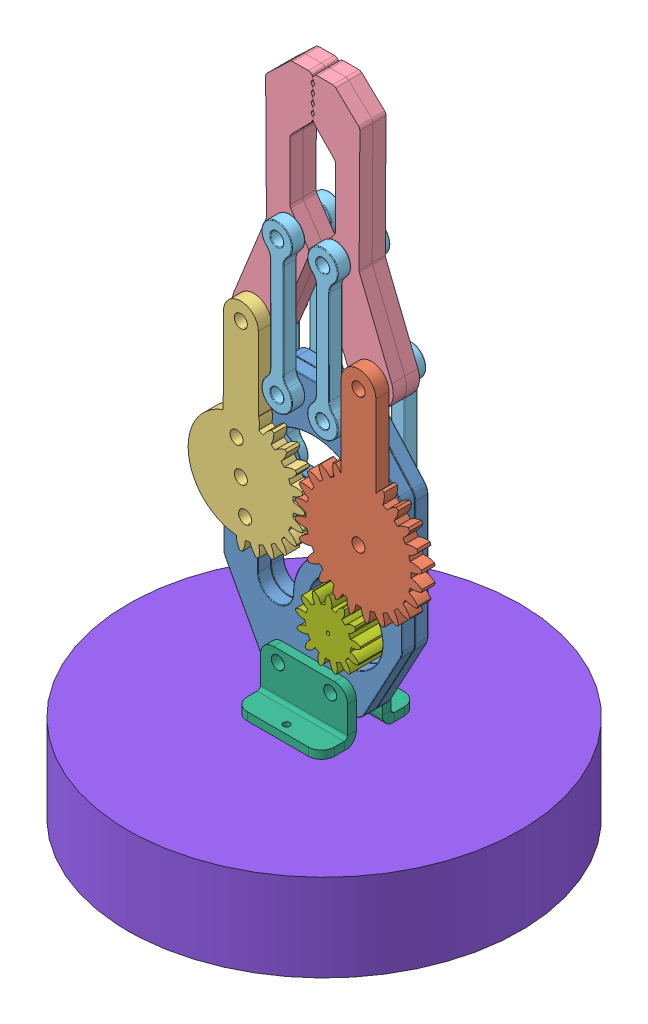
SolidWorks assembly Assem6, configuration Default. Lengths in mm.
Overall size (90 150.89 90).
26 component instances, 9 part files, 47 mates.
Components (placement in the parent):
- Part3-3-1: Part3-3 [Default] at origin size (41 62 3.03)
- part4-4-1: part4-4 [Default] at (13.5 37.5997 3) x (0 0 1) z (0 -1 0) size (3 29.07 49.54)
- part5-5-1: part5-5 [Default] at (-13.5 37.5997 6) x (0 0 -1) z (0.130526 -0.991445 0) size (3 26.63 49.27)
- Part1-1-1: Part1-1 [Default] at (-13.5 68.5997 0) x (0.374356 0.927285 0) z (0 0 1) size (60.3 20.75 3)
- Part2-2-1: Part2-2 [Default] at (-5.2398 58 4.5) x (-0.000786 1 0) z (0 0 1) size (38 7 3)
- Part2-2-2: Part2-2 [Default] at (5.2398 58 4.5) x (0.000786 1 0) z (0 0 1) size (38 7 3)
- Part1-1-2: Part1-1 [Default] at (13.5 68.5997 3) x (-0.374356 0.927285 0) z (0 0 -1) size (60.3 20.75 3)
- Part3-3-2: Part3-3 [Default] at (0 0 -3) size (41 62 3.03)
- Part1-1-3: Part1-1 [Default] at (13.5 68.5997 0) x (-0.374356 0.927285 0) z (0 0 -1) size (60.3 20.75 3)
- Part1-1-4: Part1-1 [Default] at (-13.5 68.5997 -3) x (0.374356 0.927285 0) z (0 0 1) size (60.3 20.75 3)
- Part2-2-5: Part2-2 [Default] at (-5.2398 58 -4.5) x (-0.000786 1 0) z (0 0 1) size (38 7 3)
- Part2-2-6: Part2-2 [Default] at (5.2398 58 -4.5) x (0.000786 1 0) z (0 0 1) size (38 7 3)
- Part2-2-9: Part2-2 [Default] at (13.5 37.5997 -4.5) x (0 1 0) z (0 0 1) size (38 7 3)
- Part2-2-10: Part2-2 [Default] at (-13.5 37.5997 -4.5) x (0 1 0) z (0 0 1) size (38 7 3)
- Part6-6-1: Part6-6 [Default] at (13.5 37.5997 7) x (1 0 0) z (0 1 0) (suppressed, hidden)
- Part7-7-1: Part7-7 [Default] at (0 -5.279 3) x (0 -1 0) z (-1 0 0) size (12 8 20)
- Part6-6-2: Part6-6 [Default] at (-13.5 37.5997 -7) x (-0.923728 -0.383049 0) z (-0.383049 0.923728 0) (suppressed, hidden)
- Part6-6-3: Part6-6 [Default] at (-31.0284 63.1684 -7) x (-0.923728 -0.383049 0) z (-0.383049 0.923728 0) (suppressed, hidden)
- Part6-6-4: Part6-6 [Default] at (-5.2398 58 -7) x (0.923728 0.383049 0) z (0.383049 -0.923728 0) (suppressed, hidden)
- Part6-6-5: Part6-6 [Default] at (-22.7772 83.5625 -7) x (0.923728 0.383049 0) z (0.383049 -0.923728 0) (suppressed, hidden)
- Part6-6-6: Part6-6 [Default] at (22.7772 83.5625 -7) x (0.923728 0.383049 0) z (0.383049 -0.923728 0) (suppressed, hidden)
- Part6-6-7: Part6-6 [Default] at (5.2398 58 -7) x (0.923728 0.383049 0) z (0.383049 -0.923728 0) (suppressed, hidden)
- Part6-6-8: Part6-6 [Default] at (31.0284 63.1684 -7) x (0.923728 0.383049 0) z (0.383049 -0.923728 0) (suppressed, hidden)
- Part7-7-3: Part7-7 [Default] at (0 -5.279 -3) x (0 -1 0) z (1 0 0) size (12 8 20)
- part8-8-1: part8-8 [Default] at (7.5 17.5997 7) x (0 0 -1) z (0.96731 -0.253595 0) size (13 17.5 17.5)
- Part7-1: Part7 [Default] at (1.0492 -25.1139 1.4412) size (90 20 90)
Mates (geometry in assembly coordinates):
- Concentric1: concentric aligned: cylinder of Part3-3-1 through (13.5 37.5997 3) axis (0 0 -1) radius 1.5; cylinder of part4-4-1 through (13.5 37.5997 53.0001) axis (0 0 -1) radius 1.5
- Coincident1: coincident anti-aligned: plane of Part3-3-1 through (0 0 3) normal (0 0 1); plane of part4-4-1 through (13.5 37.5997 3) normal (0 0 -1)
- Concentric2: concentric anti-aligned: cylinder of Part3-3-1 through (-13.5 37.5997 3) axis (0 0 -1) radius 1.5; cylinder of part5-5-1 through (-13.5 37.5997 -44.0001) axis (0 0 1) radius 1.5
- Coincident3: coincident anti-aligned: plane of Part3-3-1 through (0 0 3) normal (0 0 1); plane of part5-5-1 through (-13.5 37.5997 3) normal (0 0 -1)
- Concentric3: concentric aligned: cylinder of Part3-3-1 through (-5.2398 58 3) axis (0 0 -1) radius 1.5; cylinder of Part2-2-1 through (-5.2398 58 6) axis (0 0 -1) radius 1.5
- Coincident4: coincident anti-aligned: plane of Part3-3-1 through (0 0 3) normal (0 0 1); plane of Part2-2-1 through (-5.2398 58 3) normal (0 0 -1)
- Concentric4: concentric anti-aligned: cylinder of part5-5-1 through (-13.5 68.5997 3) axis (0 0 1) radius 1.5; cylinder of Part1-1-1 through (-13.5 68.5997 3) axis (0 0 -1) radius 1.5
- Concentric5: concentric aligned: cylinder of Part1-1-1 through (-5.2642 89 3) axis (0 0 -1) radius 1.5; cylinder of Part2-2-1 through (-5.2642 89 6) axis (0 0 -1) radius 1.5
- Concentric6: concentric anti-aligned: cylinder of part4-4-1 through (13.5 68.5997 6) axis (0 0 -1) radius 1.5; cylinder of Part1-1-2 through (13.5 68.5997 0) axis (0 0 1) radius 1.5
- Concentric7: concentric aligned: cylinder of Part3-3-1 through (5.2398 58 3) axis (0 0 -1) radius 1.5; cylinder of Part2-2-2 through (5.2398 58 6) axis (0 0 -1) radius 1.5
- Concentric8: concentric anti-aligned: cylinder of Part2-2-2 through (5.2642 89 6) axis (0 0 -1) radius 1.5; cylinder of Part1-1-2 through (5.2642 89 0) axis (0 0 1) radius 1.5
- Coincident8: coincident anti-aligned: plane of part4-4-1 through (13.5 37.5997 3) normal (0 0 -1); plane of Part1-1-2 through (13.5 68.5997 3) normal (0 0 1)
- Coincident9: coincident anti-aligned: plane of part5-5-1 through (-13.5 37.5997 3) normal (0 0 -1); plane of Part1-1-1 through (-13.5 68.5997 3) normal (0 0 1)
- Coincident10: coincident anti-aligned: plane of Part3-3-1 through (0 0 3) normal (0 0 1); plane of Part2-2-2 through (5.2398 58 3) normal (0 0 -1)
- Concentric11: concentric aligned: cylinder of Part3-3-2 through (13.5 37.5997 0) axis (0 0 -1) radius 1.5; cylinder of Part2-2-9 through (13.5 37.5997 -3) axis (0 0 -1) radius 1.5
- Concentric12: concentric anti-aligned: cylinder of Part1-1-3 through (13.5 68.5997 -3) axis (0 0 1) radius 1.5; cylinder of Part2-2-9 through (13.5 68.5997 -3) axis (0 0 -1) radius 1.5
- Coincident11: coincident anti-aligned: plane of Part3-3-2 through (0 0 -3) normal (0 0 -1); plane of Part2-2-9 through (13.5 37.5997 -3) normal (0 0 1)
- Concentric13: concentric aligned: cylinder of Part3-3-2 through (-13.5 37.5997 0) axis (0 0 -1) radius 1.5; cylinder of Part2-2-10 through (-13.5 37.5997 -3) axis (0 0 -1) radius 1.5
- Concentric14: concentric aligned: cylinder of Part1-1-4 through (-13.5 68.5997 0) axis (0 0 -1) radius 1.5; cylinder of Part2-2-10 through (-13.5 68.5997 -3) axis (0 0 -1) radius 1.5
- Coincident12: coincident anti-aligned: plane of Part3-3-2 through (0 0 -3) normal (0 0 -1); plane of Part2-2-10 through (-13.5 37.5997 -3) normal (0 0 1)
- Concentric15: concentric anti-aligned: cylinder of part4-4-1 through (13.5 37.5997 53.0001) axis (0 0 -1) radius 1.5; cylinder of Part6-6-1 through (13.5 37.5997 7) axis (0 0 1) radius 1.5
- Coincident15: coincident anti-aligned: plane of Part2-2-9 through (13.5 37.5997 -6) normal (0 0 -1); plane of Part6-6-1 through (11 37.5997 -6) normal (0 0 1)
- Coincident16: coincident anti-aligned: plane of Part3-3-1 through (0 0 3) normal (0 0 1); plane of Part7-7-1 through (-10 -5.279 3) normal (0 0 -1)
- Concentric16: concentric anti-aligned: cylinder of Part3-3-1 through (-6 4 3) axis (0 0 -1) radius 1.5; cylinder of Part7-7-1 through (-6 4 3) axis (0 0 1) radius 1.5
- Concentric17: concentric anti-aligned: cylinder of Part3-3-1 through (6 4 3) axis (0 0 -1) radius 1.5; cylinder of Part7-7-1 through (6 4 3) axis (0 0 1) radius 1.5
- Concentric18: concentric anti-aligned: cylinder of part5-5-1 through (-13.5 37.5997 -44.0001) axis (0 0 1) radius 1.5; cylinder of Part6-6-2 through (-13.5 37.5997 -7) axis (0 0 -1) radius 1.5
- Coincident17: coincident anti-aligned: plane of part5-5-1 through (-13.5 37.5997 6) normal (0 0 1); plane of Part6-6-2 through (-11.1907 38.5573 6) normal (0 0 -1)
- Concentric19: concentric anti-aligned: cylinder of part5-5-1 through (-31.0284 63.1684 3) axis (0 0 1) radius 1.5; cylinder of Part6-6-3 through (-31.0284 63.1684 -7) axis (0 0 -1) radius 1.5
- Coincident18: coincident anti-aligned: plane of part5-5-1 through (-13.5 37.5997 6) normal (0 0 1); plane of Part6-6-3 through (-28.719 64.126 6) normal (0 0 -1)
- Concentric20: concentric aligned: cylinder of Part2-2-1 through (-5.2398 58 6) axis (0 0 -1) radius 1.5; cylinder of Part6-6-4 through (-5.2398 58 -7) axis (0 0 -1) radius 1.5
- Coincident19: coincident anti-aligned: plane of Part2-2-1 through (-5.2398 58 6) normal (0 0 1); plane of Part6-6-4 through (-7.5491 57.0424 6) normal (0 0 -1)
- Concentric21: concentric aligned: cylinder of Part2-2-1 through (-22.7772 83.5625 6) axis (0 0 -1) radius 1.5; cylinder of Part6-6-5 through (-22.7772 83.5625 -7) axis (0 0 -1) radius 1.5
- Coincident20: coincident anti-aligned: plane of Part2-2-1 through (-5.2398 58 6) normal (0 0 1); plane of Part6-6-5 through (-25.0865 82.6048 6) normal (0 0 -1)
- Concentric22: concentric aligned: cylinder of Part2-2-2 through (22.7772 83.5625 6) axis (0 0 -1) radius 1.5; cylinder of Part6-6-6 through (22.7772 83.5625 -7) axis (0 0 -1) radius 1.5
- Coincident21: coincident anti-aligned: plane of Part2-2-2 through (5.2398 58 6) normal (0 0 1); plane of Part6-6-6 through (20.4679 82.6048 6) normal (0 0 -1)
- Concentric23: concentric aligned: cylinder of Part2-2-2 through (5.2398 58 6) axis (0 0 -1) radius 1.5; cylinder of Part6-6-7 through (5.2398 58 -7) axis (0 0 -1) radius 1.5
- Coincident22: coincident anti-aligned: plane of Part2-2-2 through (5.2398 58 6) normal (0 0 1); plane of Part6-6-7 through (2.9305 57.0424 6) normal (0 0 -1)
- Concentric24: concentric aligned: cylinder of part4-4-1 through (31.0284 63.1684 6) axis (0 0 -1) radius 1.5; cylinder of Part6-6-8 through (31.0284 63.1684 -7) axis (0 0 -1) radius 1.5
- Coincident23: coincident anti-aligned: plane of part4-4-1 through (13.5 37.5997 6) normal (0 0 1); plane of Part6-6-8 through (28.719 62.2108 6) normal (0 0 -1)
- Coincident25: coincident anti-aligned: plane of Part3-3-2 through (0 0 -3) normal (0 0 -1); plane of Part7-7-3 through (10 -5.279 -3) normal (0 0 1)
- Concentric27: concentric aligned: cylinder of Part3-3-2 through (6 4 0) axis (0 0 -1) radius 1.5; cylinder of Part7-7-3 through (6 4 -3) axis (0 0 -1) radius 1.5
- Concentric28: concentric aligned: cylinder of Part3-3-2 through (-6 4 0) axis (0 0 -1) radius 1.5; cylinder of Part7-7-3 through (-6 4 -3) axis (0 0 -1) radius 1.5
- Concentric29: concentric anti-aligned: cylinder of Part3-3-1 through (7.5 17.5997 3) axis (0 0 -1) radius 8.5; cylinder of part8-8-1 through (7.5 17.5997 -6) axis (0 0 1) radius 8.75
- Coincident26: coincident anti-aligned: plane of Part3-3-2 through (0 0 -3) normal (0 0 -1); plane of part8-8-1 through (7.5 17.5997 -3) normal (0 0 1)
- LimitAngle1: limit planar angle = 3.141593 rad anti-aligned: plane of part5-5-1 through (-17.5 37.5997 3) normal (-1 0 0); plane of Part3-3-1 through (-20.5 47.8997 3) normal (-1 0 0)
- GearMate1: gear = 1 : 1 mm: cylinder of part5-5-1 through (-13.5 37.5997 3) axis (0 0 1) radius 12.0927; cylinder of part4-4-1 through (13.5 37.5997 6) axis (0 0 -1) radius 12.0927
- GearMate2: gear = 13 : 24 mm: cylinder of part8-8-1 through (7.5 17.5997 -3) axis (0 0 1) radius 5.249; cylinder of part4-4-1 through (13.5 37.5997 6) axis (0 0 -1) radius 12.0927
